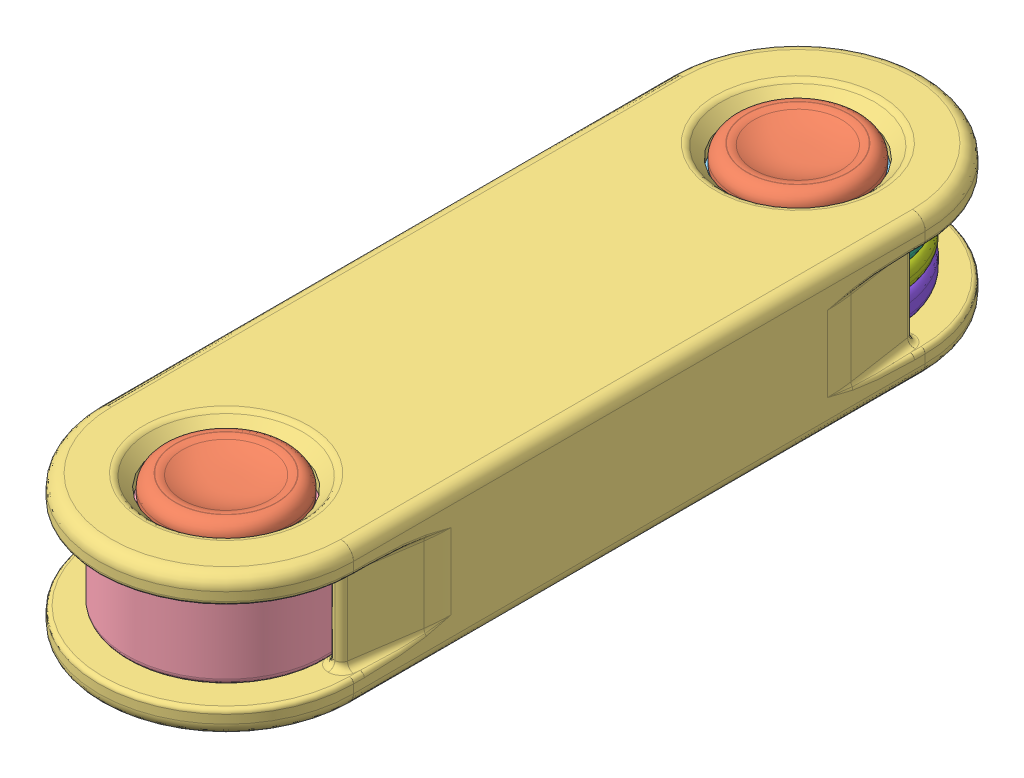
SolidWorks assembly kitTupper_00_ASSEMBLY, configuration Default. Lengths in mm.
Overall size (30.11 16.59 97.32).
16 component instances, 12 part files, 15 mates.
Components (placement in the parent):
- kitTupper_10_Unio-1: kitTupper_10_Unio [Default] at origin size (15 16.59 15)
  - kitTupper_11C01_Casquet-1: kitTupper_11C01_Casquet [Default] at origin size (15 13.5 15)
  - kitTupper_12C01_Mascle-1: kitTupper_12C01_Mascle [Default] at origin size (15 16.59 15)
- kitTupper_10_Unio-2: kitTupper_10_Unio [Default] at (0 0 67.3226) size (15 16.59 15)
  - kitTupper_11C01_Casquet-1: kitTupper_11C01_Casquet [Default] at origin size (15 13.5 15)
  - kitTupper_12C01_Mascle-1: kitTupper_12C01_Mascle [Default] at origin size (15 16.59 15)
- kitTupper_05C01_Carcassa fixe-1: kitTupper_05C01_Carcassa fixe [Default] at origin size (30.07 16.5 97.32)
- kitTupper_06C01_Carcassa movil-2: kitTupper_06C01_Carcassa movil [Default] at origin size (26.74 11.5 75.72)
- kitTupper_01C01_Llevataps_2.5mm-1: kitTupper_01C01_Llevataps_2.5mm [Default] at origin size (23 2.5 63.82) (hidden)
- kitTupper_02C01_Ganivet_2.5mm-1: kitTupper_02C01_Ganivet_2.5mm [Default] at origin size (24.8 4.54 63.03) (hidden)
- kitTupper_03C01_Forquilla_2.5mm-1: kitTupper_03C01_Forquilla_2.5mm [Default] at origin size (23.4 2.5 60.9) (hidden)
- kitTupper_04C01_Cullera_3mm-1: kitTupper_04C01_Cullera_3mm [Default] at origin size (23.4 3.56 64.01) (hidden)
- kitTupper_01C02_Llevataps_2.52mm-1: kitTupper_01C02_Llevataps_2.52mm [Default] at origin size (23 2.52 63.82)
- kitTupper_02C02_Ganivet_2.52mm-1: kitTupper_02C02_Ganivet_2.52mm [Default] at origin size (24.8 4.56 63.03)
- kitTupper_03C02_Forquilla_2.52mm-1: kitTupper_03C02_Forquilla_2.52mm [Default] at origin size (23.4 2.52 60.9)
- kitTupper_04C02_Cullera_3.20mm-1: kitTupper_04C02_Cullera_3.20mm [Default] at origin size (23.4 4.11 64.01)
Mates (geometry in assembly coordinates):
- Coincident1: coordinate: point of Assem1^kitTupper_00_ASSEMBLY-1
- Coincident3: coordinate: unknown of Part2^kitTupper_00_ASSEMBLY-1
- Coincident4: coordinate: unknown of Part3^kitTupper_00_ASSEMBLY-1
- Concentric1: concentric anti-aligned: cylinder of kitTupper_05_Carcassa fixe-1 through (0 25.5 67.3226) axis (0 -1 0) radius 7.8; cylinder of kitTupper_10_Unio-2/kitTupper_11_Casquet-1 through (0 21.1791 67.3226) axis (0 1 0) radius 5
- Coincident5: coincident aligned: plane of kitTupper_10_Unio-1/kitTupper_11_Casquet-1 through (0 0 3) normal (0 -1 0); plane of kitTupper_10_Unio-2/kitTupper_11_Casquet-1 through (0 0 70.3226) normal (0 -1 0)
- Coincident6: coordinate: unknown of kitTupper_05_Carcassa fixe-1
- Coincident7: coordinate: unknown of Part4^kitTupper_00_ASSEMBLY-1
- Concentric2: concentric anti-aligned: cylinder of kitTupper_10_Unio-2/kitTupper_11_Casquet-1 through (0 21.1791 67.3226) axis (0 1 0) radius 5; cylinder of kitTupper_06_Carcassa movil_6-2 through (0 13.5 67.3226) axis (0 -1 0) radius 5.4
- Width1: width anti-aligned: plane of kitTupper_05_Carcassa fixe-1 through (0 13.5 0) normal (0 -1 0); plane of kitTupper_05_Carcassa fixe-1 through (0 3 0) normal (0 1 0); plane of kitTupper_06C01_Carcassa movil_a testa-tolerancia suau-2 through (-7.1623 13.5 52.4163) normal (0 1 0); plane of kitTupper_06C01_Carcassa movil_a testa-tolerancia suau-2 through (-7.1623 3 52.4163) normal (0 -1 0)
- Coincident11: coordinate: unknown of kitTupper_04_Cullera-1
- Coincident12: coordinate: unknown of kitTupper_03_Forquilla-1
- LimitAngle1: limit planar angle = 0 rad: plane of assembly through (0 0 0) normal (1 0 0); plane of kitTupper_06_Carcassa movil_6-2 through (0 0 0) normal (1 0 0)
- Distance1: distance = 4.94 mm anti-aligned: plane of kitTupper_05_Carcassa fixe-1 through (0 13.5 0) normal (0 -1 0); plane of kitTupper_03_Forquilla-1 through (0 8.5 0) normal (0 1 0)
- Concentric3: concentric aligned: cylinder of kitTupper_05_Carcassa fixe-1 through (0 16.5 0) axis (0 -1 0) radius 15; cylinder of kitTupper_03_Forquilla-1 through (0 18.2 0) axis (0 -1 0) radius 5.7
- Parallel1: parallel aligned: plane of kitTupper_05_Carcassa fixe-1 through (-15 16.5 0) normal (-1 0 0); plane of kitTupper_03_Forquilla-1
